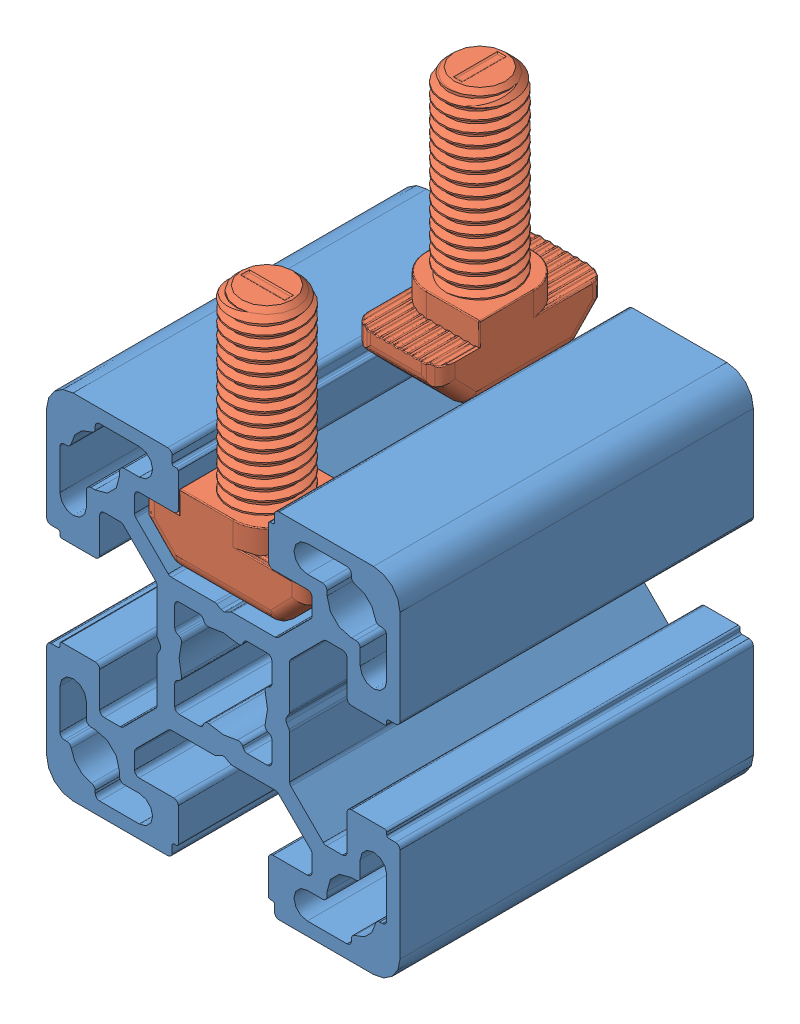
SolidWorks assembly Сборка Т-Гайка паз10, configuration По умолчанию. Lengths in mm.
Overall size (40 66.02 40.01).
3 component instances, 2 part files, 5 mates.
Components (placement in the parent):
- 40х40-1: 40х40 [По умолчанию] at origin size (40 40 40)
- Т-Болт 10 паз-1: Т-Болт 10 паз [По умолчанию] at (0 8.4 35.05) size (19 28.21 9.91)
- Т-Болт 10 паз-2: Т-Болт 10 паз [По умолчанию] at (0.05 17.8115 11.0058) x (0 0 -1) z (1 0 0) size (19 28.21 9.91)
Mates (geometry in assembly coordinates):
- Совпадение1: coincident aligned: plane of Т-Гайка 10 паз-1 through (5 14 30.1) normal (1 0 0); plane of Т-Гайка 10 паз-2 through (5 17.8115 11.0058) normal (1 0 0)
- Параллельность1: parallel anti-aligned: plane of Т-Гайка 10 паз-1 through (-5 16.6 30.1) normal (0 1 0); plane of Т-Гайка 10 паз-2 through (-4.9 17.8115 5.0058) normal (0 -1 0)
- Совпадение3: coincident aligned: plane of 40х40-1 through (0 0 40) normal (0 0 1); plane of Т-Гайка 10 паз-1 through (0 8.4 40) normal (0 0 1)
- Совпадение4: coincident anti-aligned: plane of 40х40-1 through (0 14 40) normal (0 -1 0); plane of Т-Гайка 10 паз-1 through (-9.5 14 30.1) normal (0 1 0)
- Расстояние1: distance = 0.1 mm anti-aligned: plane of 40х40-1 through (-5.1 0 40) normal (1 0 0); plane of Т-Гайка 10 паз-1 through (-5 14 30.1) normal (-1 0 0)
